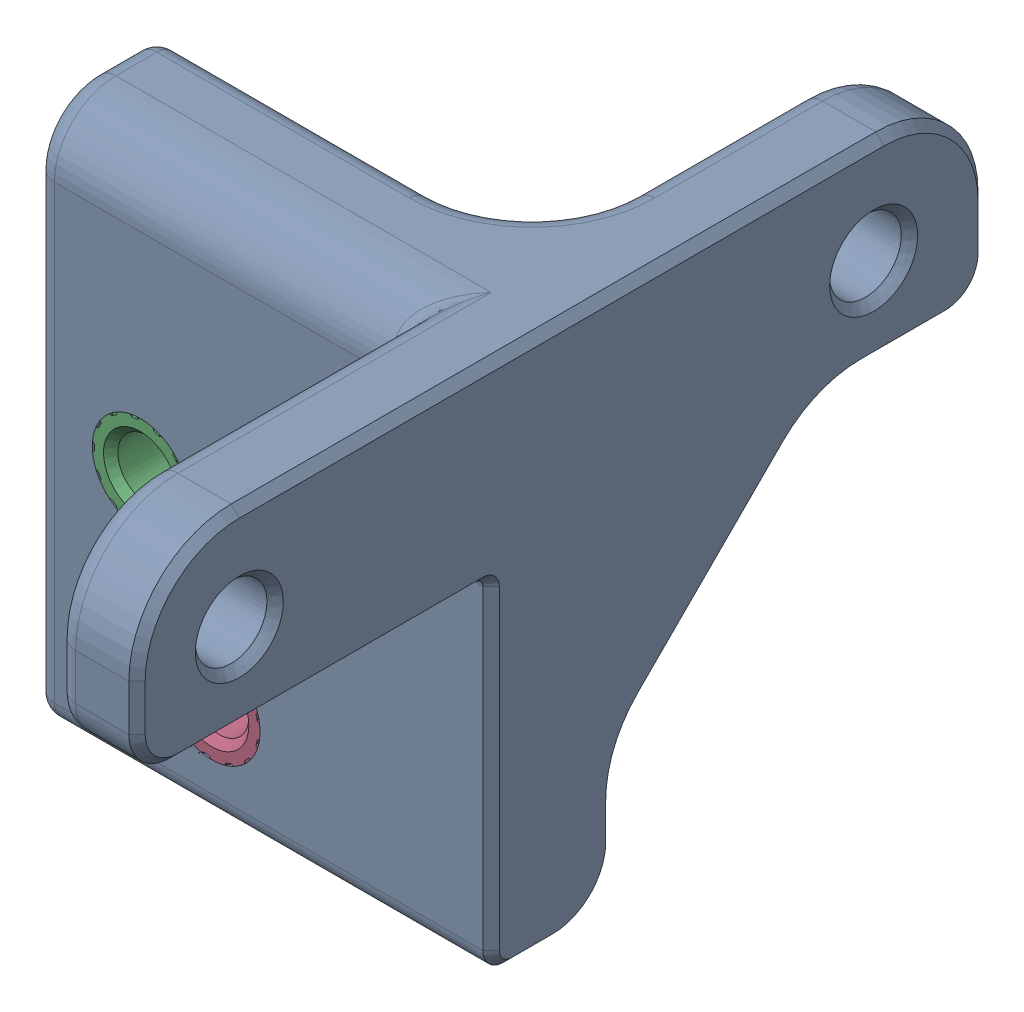
SolidWorks assembly Chain Anchor, configuration Default. Lengths in mm.
Overall size (22.44 26.26 41.5).
4 component instances, 2 part files, 0 mates.
Components (placement in the parent):
- Chain Anchor-1: Chain Anchor [Default] at origin size (22.44 26.26 41.5)
- M3 Threaded Insert (1)-1: M3 Threaded Insert (1) [Default] at (-82.8691 135.7902 63.5121) x (0 1 0) z (0 0 1) size (5 5 3.85)
- M3 Threaded Insert (1)-2: M3 Threaded Insert (1) [Default] at (-89.8691 135.7902 63.5121) x (0 1 0) z (0 0 1) size (5 5 3.85)
- M3 Threaded Insert (1)-3: M3 Threaded Insert (1) [Default] at (-86.3691 127.7902 63.5121) x (0 1 0) z (0 0 1) size (5 5 3.85)
